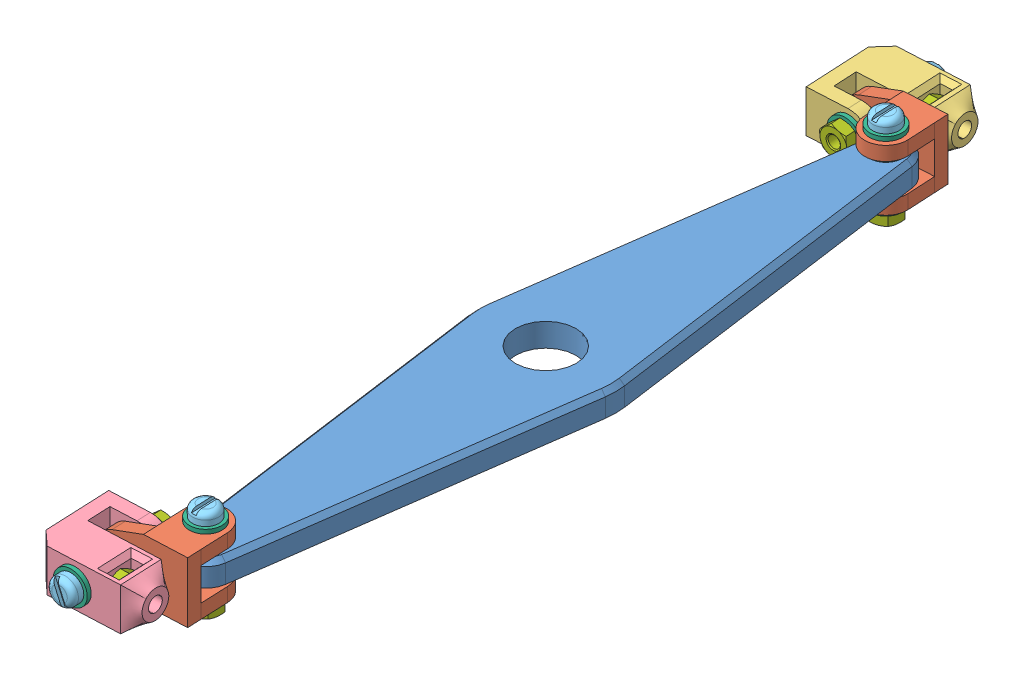
SolidWorks assembly diffSub, configuration Default. Lengths in mm.
Overall size (34.06 19.68 191.16).
31 component instances, 7 part files, 62 mates.
Components (placement in the parent):
- differentialBar-1: differentialBar [Default] at (-60.7169 0 132.4054) x (1 0 0) z (0 1 0) size (30 156 5)
- differentialHinge-1: differentialHinge [Default] at (109.4283 6 -8.048) x (-0.998631 0 0.052313) z (0 1 0) size (18.65 13.57 13)
- rodHinge-diff-left-1: rodHinge-diff-left [Default] at (109.4846 0 -6.9452) x (0.998698 0 -0.051019) z (0.051019 0 0.998698) size (21.11 9.1 17.1)
- rodHinge-diff-right-1: rodHinge-diff-right [Default] at (109.6477 0 143.6584) x (0.99903 0 -0.044035) z (0.044035 0 0.99903) size (21.11 9.1 17.1)
- differentialHinge-2: differentialHinge [Default] at (108.9918 -1 128.777) x (-0.999086 0 0.042741) z (0 -1 0) size (18.65 13.57 13)
- pan slot head_am-1: pan slot head_am [B18.6.7M - M3 x 0.5 x 16 Slotted PHMS --16C] at (24.2831 12.3 137.4054) x (0 -1 0) z (0.041653 0 0.999132) size (18.48 5.6 5.6)
- flat washer narrow_am-1: flat washer narrow_am [B18.22M - Plain washer, 3 mm, narrow] at (24.2831 -4 137.4054) x (0 1 0) z (0.078866 0 0.996885) size (0.9 7 7)
- flat washer narrow_am-2: flat washer narrow_am [B18.22M - Plain washer, 3 mm, narrow] at (24.2831 -0.1 137.4054) x (0 1 0) z (0.163698 0 0.98651) size (0.9 7 7)
- flat washer narrow_am-3: flat washer narrow_am [B18.22M - Plain washer, 3 mm, narrow] at (24.2831 6 137.4054) x (0 1 0) z (0 0 1) size (0.9 7 7)
- flat washer narrow_am-4: flat washer narrow_am [B18.22M - Plain washer, 3 mm, narrow] at (24.2831 9 137.4054) x (0 -1 0) z (0 0 1) size (0.9 7 7)
- hex nut style 1_am-1: hex nut style 1_am [B18.2.4.1M - Hex nut, Style 1,  M3 x 0.5 --D-C] at (24.2831 -7.3 137.4054) x (0.988879 0 0.148724) z (0 -1 0) size (5.5 6.35 2.4)
- pan slot head_am-2: pan slot head_am [B18.6.7M - M3 x 0.5 x 16 Slotted PHMS --16C] at (24.2831 12.3 -8.5946) x (0 -1 0) z (0.041653 0 0.999132) size (18.48 5.6 5.6)
- flat washer narrow_am-5: flat washer narrow_am [B18.22M - Plain washer, 3 mm, narrow] at (24.2831 -4 -8.5946) x (0 1 0) z (0.078866 0 0.996885) size (0.9 7 7)
- flat washer narrow_am-6: flat washer narrow_am [B18.22M - Plain washer, 3 mm, narrow] at (24.2831 -0.1 -8.5946) x (0 1 0) z (0.163698 0 0.98651) size (0.9 7 7)
- flat washer narrow_am-7: flat washer narrow_am [B18.22M - Plain washer, 3 mm, narrow] at (24.2831 6 -8.5946) x (0 1 0) z (0 0 1) size (0.9 7 7)
- flat washer narrow_am-8: flat washer narrow_am [B18.22M - Plain washer, 3 mm, narrow] at (24.2831 9 -8.5946) x (0 -1 0) z (0 0 1) size (0.9 7 7)
- hex nut style 1_am-2: hex nut style 1_am [B18.2.4.1M - Hex nut, Style 1,  M3 x 0.5 --D-C] at (24.2831 -7.3 -8.5946) x (0.988879 0 0.148724) z (0 -1 0) size (5.5 6.35 2.4)
- pan slot head_am-3: pan slot head_am [B18.6.7M - M3 x 0.5 x 16 Slotted PHMS --16C] at (15.7213 2.5 160.2105) x (-0.044035 0 -0.99903) z (-0.385521 0.922543 0.016993) size (18.48 5.6 5.6)
- flat washer narrow_am-9: flat washer narrow_am [B18.22M - Plain washer, 3 mm, narrow] at (14.8229 2.5 139.8302) x (0.044035 0 0.99903) z (0.419607 -0.907517 -0.018495) size (0.9 7 7)
- flat washer narrow_am-10: flat washer narrow_am [B18.22M - Plain washer, 3 mm, narrow] at (14.9947 2.5 143.7265) x (0.044035 0 0.99903) z (-0.495488 0.86834 0.02184) size (0.9 7 7)
- flat washer narrow_am-11: flat washer narrow_am [B18.22M - Plain washer, 3 mm, narrow] at (15.1752 2.5 147.8225) x (0.044035 0 0.99903) z (-0.346797 0.937816 0.015286) size (0.9 7 7)
- flat washer narrow_am-12: flat washer narrow_am [B18.22M - Plain washer, 3 mm, narrow] at (15.5759 2.5 156.9137) x (-0.044035 0 -0.99903) z (0.346797 -0.937816 -0.015286) size (0.9 7 7)
- hex nut style 1_am-3: hex nut style 1_am [B18.2.4.1M - Hex nut, Style 1,  M3 x 0.5 --D-C] at (14.6776 2.5 136.5334) x (-0.978063 -0.203798 0.043111) z (-0.044035 0 -0.99903) size (5.5 6.35 2.4)
- pan slot head_am-4: pan slot head_am [B18.6.7M - M3 x 0.5 x 16 Slotted PHMS --16C] at (13.5947 2.5 -30.4836) x (0.051019 0 0.998698) z (-0.009364 0.999956 0.000478) size (18.48 5.6 5.6)
- flat washer narrow_am-13: flat washer narrow_am [B18.22M - Plain washer, 3 mm, narrow] at (14.6355 2.5 -10.1102) x (-0.051019 0 -0.998698) z (0.027867 0.999611 -0.001424) size (0.9 7 7)
- flat washer narrow_am-14: flat washer narrow_am [B18.22M - Plain washer, 3 mm, narrow] at (14.4365 2.5 -14.0051) x (-0.051019 0 -0.998698) z (0.113006 0.993577 -0.005773) size (0.9 7 7)
- flat washer narrow_am-15: flat washer narrow_am [B18.22M - Plain washer, 3 mm, narrow] at (14.2273 2.5 -18.0998) x (-0.051019 0 -0.998698) z (-0.050953 0.998698 0.002603) size (0.9 7 7)
- flat washer narrow_am-16: flat washer narrow_am [B18.22M - Plain washer, 3 mm, narrow] at (13.763 2.5 -27.1879) x (0.051019 0 0.998698) z (-0.050953 0.998698 0.002603) size (0.9 7 7)
- hex nut style 1_am-4: hex nut style 1_am [B18.2.4.1M - Hex nut, Style 1,  M3 x 0.5 --D-C] at (14.8038 2.5 -6.8145) x (0.978727 0.198982 -0.049999) z (0.051019 0 0.998698) size (5.5 6.35 2.4)
- hex nut style 1_am-5: hex nut style 1_am [B18.2.4.1M - Hex nut, Style 1,  M3 x 0.5 --D-C] at (21.4355 2.5 -23.024) x (-0.051019 0 -0.998698) z (0.998698 0 -0.051019) size (5.5 6.35 2.4)
- hex nut style 1_am-6: hex nut style 1_am [B18.2.4.1M - Hex nut, Style 1,  M3 x 0.5 --D-C] at (22.8184 2.5 152.04) x (-0.044035 0 -0.99903) z (0.99903 0 -0.044035) size (5.5 6.35 2.4)
Mates (geometry in assembly coordinates):
- Concentric1: concentric anti-aligned: cylinder of differentialBar-1 through (24.2831 -0.001 137.4054) axis (0 1 0) radius 1.55; cylinder of differentialHinge-2 through (24.2831 9 137.4054) axis (0 -1 0) radius 1.55
- Distance1: distance = 1 mm anti-aligned: plane of differentialHinge-2 through (24.2831 6 137.4054) normal (0 -1 0); plane of differentialBar-1 through (-60.7169 5 132.4054) normal (0 1 0)
- Concentric2: concentric anti-aligned: cylinder of rodHinge-diff-right-1 through (14.8229 2.5 139.8302) axis (0.044035 0 0.99903) radius 1.55; cylinder of differentialHinge-2 through (15.1312 2.5 146.8235) axis (-0.044035 0 -0.99903) radius 1.55
- Distance2: distance = 1 mm anti-aligned: plane of rodHinge-diff-right-1 through (109.4275 0 138.6632) normal (0.044035 0 0.99903); plane of differentialHinge-2 through (109.4715 -1 139.6622) normal (-0.044035 0 -0.99903)
- Concentric3: concentric anti-aligned: cylinder of differentialBar-1 through (24.2831 -0.001 -8.5946) axis (0 1 0) radius 1.55; cylinder of differentialHinge-1 through (24.2831 9 -8.5946) axis (0 -1 0) radius 1.55
- Distance3: distance = 1 mm anti-aligned: plane of differentialHinge-1 through (109.4283 6 -8.048) normal (0 -1 0); plane of differentialBar-1 through (-60.7169 5 132.4054) normal (0 1 0)
- Concentric4: concentric anti-aligned: cylinder of differentialHinge-1 through (14.2783 2.5 -17.1011) axis (0.051019 0 0.998698) radius 1.55; cylinder of rodHinge-diff-left-1 through (14.6355 2.5 -10.1102) axis (-0.051019 0 -0.998698) radius 1.55
- Distance4: distance = 1 mm anti-aligned: plane of rodHinge-diff-left-1 through (108.9234 0 -17.9309) normal (-0.051019 0 -0.998698); plane of differentialHinge-1 through (108.8724 6 -18.9296) normal (0.051019 0 0.998698)
- Coincident2: coincident anti-aligned: plane of pan slot head_am-1 through (25.7818 9.9 137.3429) normal (0 -1 0); plane of flat washer narrow_am-4 through (27.7831 9.9 137.4054) normal (0 1 0)
- Concentric5: concentric aligned: cylinder of pan slot head_am-1 through (24.2831 37.7 137.4054) axis (0 1 0) radius 1.5; cylinder of flat washer narrow_am-4 through (24.2831 43.925 137.4054) axis (0 1 0) radius 1.84
- Concentric6: concentric anti-aligned: cylinder of pan slot head_am-1 through (24.2831 37.7 137.4054) axis (0 1 0) radius 1.5; cylinder of flat washer narrow_am-1 through (24.2831 -38.925 137.4054) axis (0 -1 0) radius 1.84
- Concentric7: concentric anti-aligned: cylinder of pan slot head_am-1 through (24.2831 37.7 137.4054) axis (0 1 0) radius 1.5; cylinder of flat washer narrow_am-2 through (24.2831 -35.025 137.4054) axis (0 -1 0) radius 1.84
- Concentric8: concentric anti-aligned: cylinder of pan slot head_am-1 through (24.2831 37.7 137.4054) axis (0 1 0) radius 1.5; cylinder of flat washer narrow_am-3 through (24.2831 -28.925 137.4054) axis (0 -1 0) radius 1.84
- Concentric9: concentric aligned: cylinder of differentialBar-1 through (24.2831 -0.001 137.4054) axis (0 1 0) radius 1.55; cylinder of pan slot head_am-1 through (24.2831 37.7 137.4054) axis (0 1 0) radius 1.5
- Coincident3: coincident anti-aligned: plane of differentialHinge-2 through (109.6037 9 142.6593) normal (0 1 0); plane of flat washer narrow_am-4 through (26.1231 9 137.4054) normal (0 -1 0)
- Coincident4: coincident anti-aligned: plane of differentialHinge-2 through (24.2831 6 137.4054) normal (0 -1 0); plane of flat washer narrow_am-3 through (22.4431 6 137.4054) normal (0 1 0)
- Coincident5: coincident anti-aligned: plane of differentialHinge-2 through (108.9918 -1 128.777) normal (0 1 0); plane of flat washer narrow_am-2 through (20.8303 -1 137.9784) normal (0 -1 0)
- Coincident6: coincident anti-aligned: plane of differentialHinge-2 through (108.9918 -4 128.777) normal (0 -1 0); plane of flat washer narrow_am-1 through (22.4489 -4 137.5505) normal (0 1 0)
- Concentric10: concentric anti-aligned: cylinder of pan slot head_am-1 through (24.2831 37.7 137.4054) axis (0 1 0) radius 1.5; cylinder of hex nut style 1_am-1 through (24.2831 -4.9 137.4054) axis (0 -1 0) radius 1.25
- Coincident7: coincident anti-aligned: plane of flat washer narrow_am-1 through (20.794 -4.9 137.6815) normal (0 -1 0); plane of hex nut style 1_am-1 through (23.8109 -4.9 140.5455) normal (0 1 0)
- Coincident8: coincident anti-aligned: plane of pan slot head_am-2 through (25.7818 9.9 -8.6571) normal (0 -1 0); plane of flat washer narrow_am-8 through (27.7831 9.9 -8.5946) normal (0 1 0)
- Concentric11: concentric aligned: cylinder of pan slot head_am-2 through (24.2831 37.7 -8.5946) axis (0 1 0) radius 1.5; cylinder of flat washer narrow_am-8 through (24.2831 43.925 -8.5946) axis (0 1 0) radius 1.84
- Concentric12: concentric anti-aligned: cylinder of pan slot head_am-2 through (24.2831 37.7 -8.5946) axis (0 1 0) radius 1.5; cylinder of flat washer narrow_am-5 through (24.2831 -38.925 -8.5946) axis (0 -1 0) radius 1.84
- Concentric13: concentric anti-aligned: cylinder of pan slot head_am-2 through (24.2831 37.7 -8.5946) axis (0 1 0) radius 1.5; cylinder of flat washer narrow_am-6 through (24.2831 -35.025 -8.5946) axis (0 -1 0) radius 1.84
- Concentric14: concentric anti-aligned: cylinder of pan slot head_am-2 through (24.2831 37.7 -8.5946) axis (0 1 0) radius 1.5; cylinder of flat washer narrow_am-7 through (24.2831 -28.925 -8.5946) axis (0 -1 0) radius 1.84
- Concentric15: concentric anti-aligned: cylinder of pan slot head_am-2 through (24.2831 37.7 -8.5946) axis (0 1 0) radius 1.5; cylinder of hex nut style 1_am-2 through (24.2831 -4.9 -8.5946) axis (0 -1 0) radius 1.25
- Coincident9: coincident anti-aligned: plane of flat washer narrow_am-5 through (20.794 -4.9 -8.3185) normal (0 -1 0); plane of hex nut style 1_am-2 through (23.8109 -4.9 -5.4545) normal (0 1 0)
- Concentric16: concentric aligned: cylinder of differentialBar-1 through (24.2831 -0.001 -8.5946) axis (0 1 0) radius 1.55; cylinder of pan slot head_am-2 through (24.2831 37.7 -8.5946) axis (0 1 0) radius 1.5
- Coincident10: coincident anti-aligned: plane of differentialHinge-1 through (109.4283 9 -8.048) normal (0 1 0); plane of flat washer narrow_am-8 through (26.1231 9 -8.5946) normal (0 -1 0)
- Coincident11: coincident anti-aligned: plane of differentialHinge-1 through (109.4283 6 -8.048) normal (0 -1 0); plane of flat washer narrow_am-7 through (22.4431 6 -8.5946) normal (0 1 0)
- Coincident12: coincident anti-aligned: plane of differentialHinge-1 through (24.2831 -1 -8.5946) normal (0 1 0); plane of flat washer narrow_am-6 through (20.8303 -1 -8.0216) normal (0 -1 0)
- Coincident13: coincident anti-aligned: plane of differentialHinge-1 through (108.7194 -4 -21.9257) normal (0 -1 0); plane of flat washer narrow_am-5 through (22.4489 -4 -8.4495) normal (0 1 0)
- Coincident14: coincident anti-aligned: plane of pan slot head_am-3 through (14.2331 1.9212 157.8737) normal (-0.044035 0 -0.99903); plane of flat washer narrow_am-12 through (18.8947 3.715 157.6682) normal (0.044035 0 0.99903)
- Concentric17: concentric aligned: cylinder of pan slot head_am-3 through (16.8397 2.5 185.5858) axis (0.044035 0 0.99903) radius 1.5; cylinder of flat washer narrow_am-12 through (17.1139 2.5 191.8048) axis (0.044035 0 0.99903) radius 1.84
- Concentric18: concentric anti-aligned: cylinder of pan slot head_am-3 through (16.8397 2.5 185.5858) axis (0.044035 0 0.99903) radius 1.5; cylinder of flat washer narrow_am-9 through (13.285 2.5 104.9391) axis (-0.044035 0 -0.99903) radius 1.84
- Concentric19: concentric anti-aligned: cylinder of pan slot head_am-3 through (16.8397 2.5 185.5858) axis (0.044035 0 0.99903) radius 1.5; cylinder of flat washer narrow_am-10 through (13.4568 2.5 108.8353) axis (-0.044035 0 -0.99903) radius 1.84
- Concentric20: concentric anti-aligned: cylinder of pan slot head_am-3 through (16.8397 2.5 185.5858) axis (0.044035 0 0.99903) radius 1.5; cylinder of flat washer narrow_am-11 through (13.6373 2.5 112.9314) axis (-0.044035 0 -0.99903) radius 1.84
- Concentric21: concentric anti-aligned: cylinder of pan slot head_am-3 through (16.8397 2.5 185.5858) axis (0.044035 0 0.99903) radius 1.5; cylinder of hex nut style 1_am-3 through (14.7833 2.5 138.9311) axis (-0.044035 0 -0.99903) radius 1.25
- Coincident15: coincident anti-aligned: plane of flat washer narrow_am-9 through (11.6101 1.0299 139.071) normal (-0.044035 0 -0.99903); plane of hex nut style 1_am-3 through (14.1368 5.6088 138.9596) normal (0.044035 0 0.99903)
- Concentric22: concentric anti-aligned: cylinder of rodHinge-diff-right-1 through (15.5759 2.5 156.9137) axis (-0.044035 0 -0.99903) radius 1.55; cylinder of pan slot head_am-3 through (16.8397 2.5 185.5858) axis (0.044035 0 0.99903) radius 1.5
- Coincident16: coincident anti-aligned: plane of rodHinge-diff-right-1 through (110.0484 0 152.7495) normal (0.044035 0 0.99903); plane of flat washer narrow_am-12 through (17.2998 3.1387 156.8377) normal (-0.044035 0 -0.99903)
- Coincident17: coincident anti-aligned: plane of rodHinge-diff-right-1 through (109.6477 0 143.6584) normal (-0.044035 0 -0.99903); plane of flat washer narrow_am-11 through (16.8991 3.1387 147.7465) normal (0.044035 0 0.99903)
- Coincident18: coincident anti-aligned: plane of rodHinge-diff-right-1 through (109.4275 0 138.6632) normal (0.044035 0 0.99903); plane of flat washer narrow_am-10 through (17.9913 4.2359 142.6935) normal (-0.044035 0 -0.99903)
- Coincident19: coincident anti-aligned: plane of rodHinge-diff-right-1 through (6.2812 7.05 140.2067) normal (-0.044035 0 -0.99903); plane of flat washer narrow_am-9 through (13.1547 1.7272 139.9038) normal (0.044035 0 0.99903)
- Coincident20: coincident anti-aligned: plane of pan slot head_am-4 through (15.2151 2.5141 -28.1633) normal (0.051019 0 0.998698); plane of flat washer narrow_am-16 through (17.208 2.6786 -28.2651) normal (-0.051019 0 -0.998698)
- Concentric23: concentric aligned: cylinder of pan slot head_am-4 through (12.2988 2.5 -55.8506) axis (-0.051019 0 -0.998698) radius 1.5; cylinder of flat washer narrow_am-16 through (11.9812 2.5 -62.0675) axis (-0.051019 0 -0.998698) radius 1.84
- Concentric24: concentric anti-aligned: cylinder of pan slot head_am-4 through (12.2988 2.5 -55.8506) axis (-0.051019 0 -0.998698) radius 1.5; cylinder of flat washer narrow_am-13 through (16.4173 2.5 24.7693) axis (0.051019 0 0.998698) radius 1.84
- Concentric25: concentric anti-aligned: cylinder of pan slot head_am-4 through (12.2988 2.5 -55.8506) axis (-0.051019 0 -0.998698) radius 1.5; cylinder of flat washer narrow_am-14 through (16.2183 2.5 20.8744) axis (0.051019 0 0.998698) radius 1.84
- Concentric26: concentric anti-aligned: cylinder of pan slot head_am-4 through (12.2988 2.5 -55.8506) axis (-0.051019 0 -0.998698) radius 1.5; cylinder of flat washer narrow_am-15 through (16.0091 2.5 16.7797) axis (0.051019 0 0.998698) radius 1.84
- Concentric27: concentric anti-aligned: cylinder of pan slot head_am-4 through (12.2988 2.5 -55.8506) axis (-0.051019 0 -0.998698) radius 1.5; cylinder of hex nut style 1_am-4 through (14.6814 2.5 -9.2114) axis (0.051019 0 0.998698) radius 1.25
- Coincident21: coincident anti-aligned: plane of flat washer narrow_am-13 through (11.1873 2.5977 -9.0329) normal (0.051019 0 0.998698); plane of hex nut style 1_am-4 through (14.0503 5.6119 -9.1792) normal (-0.051019 0 -0.998698)
- Concentric28: concentric anti-aligned: cylinder of rodHinge-diff-left-1 through (13.763 2.5 -27.1879) axis (0.051019 0 0.998698) radius 1.55; cylinder of pan slot head_am-4 through (12.2988 2.5 -55.8506) axis (-0.051019 0 -0.998698) radius 1.5
- Coincident22: coincident anti-aligned: plane of rodHinge-diff-left-1 through (108.2041 0 -32.0125) normal (-0.051019 0 -0.998698); plane of flat washer narrow_am-16 through (15.5982 2.5939 -27.2817) normal (0.051019 0 0.998698)
- Coincident23: coincident anti-aligned: plane of rodHinge-diff-left-1 through (108.6683 0 -22.9244) normal (0.051019 0 0.998698); plane of flat washer narrow_am-15 through (12.3921 2.4061 -18.006) normal (-0.051019 0 -0.998698)
- Coincident24: coincident anti-aligned: plane of rodHinge-diff-left-1 through (108.9234 0 -17.9309) normal (-0.051019 0 -0.998698); plane of flat washer narrow_am-14 through (11.0094 2.896 -12.9289) normal (0.051019 0 0.998698)
- Coincident25: coincident anti-aligned: plane of rodHinge-diff-left-1 through (6.0966 7.05 -9.674) normal (0.051019 0 0.998698); plane of flat washer narrow_am-13 through (12.7986 2.5513 -10.0164) normal (-0.051019 0 -0.998698)
- Coincident26: coincident anti-aligned: plane of rodHinge-diff-left-1 through (19.2276 1.4636 -19.2014) normal (-0.02551 0.866025 -0.499349); plane of hex nut style 1_am-5 through (19.1789 0.9123 -20.1551) normal (0.02551 -0.866025 0.499349)
- Coincident27: coincident anti-aligned: plane of rodHinge-diff-left-1 through (19.1978 -2.4768 -19.7856) normal (0.02551 0.866025 0.499349); plane of hex nut style 1_am-5 through (19.0386 -0.6754 -22.9015) normal (-0.02551 -0.866025 -0.499349)
- Coincident28: coincident anti-aligned: plane of rodHinge-diff-left-1 through (19.2707 0 -18.3574) normal (0.998698 0 -0.051019); plane of hex nut style 1_am-5 through (19.0386 5.6754 -22.9015) normal (-0.998698 0 0.051019)
- Coincident29: coincident anti-aligned: plane of rodHinge-diff-right-1 through (20.2833 -2.4768 149.0287) normal (-0.022017 0.866025 -0.499515); plane of hex nut style 1_am-6 through (20.5418 0.9123 154.893) normal (0.022017 -0.866025 0.499515)
- Coincident30: coincident anti-aligned: plane of rodHinge-diff-right-1 through (20.2575 1.4636 148.4443) normal (0.022017 0.866025 0.499515); plane of hex nut style 1_am-6 through (20.4207 -0.6754 152.1457) normal (-0.022017 -0.866025 -0.499515)
- Coincident31: coincident anti-aligned: plane of rodHinge-diff-right-1 through (20.2203 0 147.6001) normal (0.99903 0 -0.044035); plane of hex nut style 1_am-6 through (20.4207 5.6754 152.1457) normal (-0.99903 0 0.044035)
